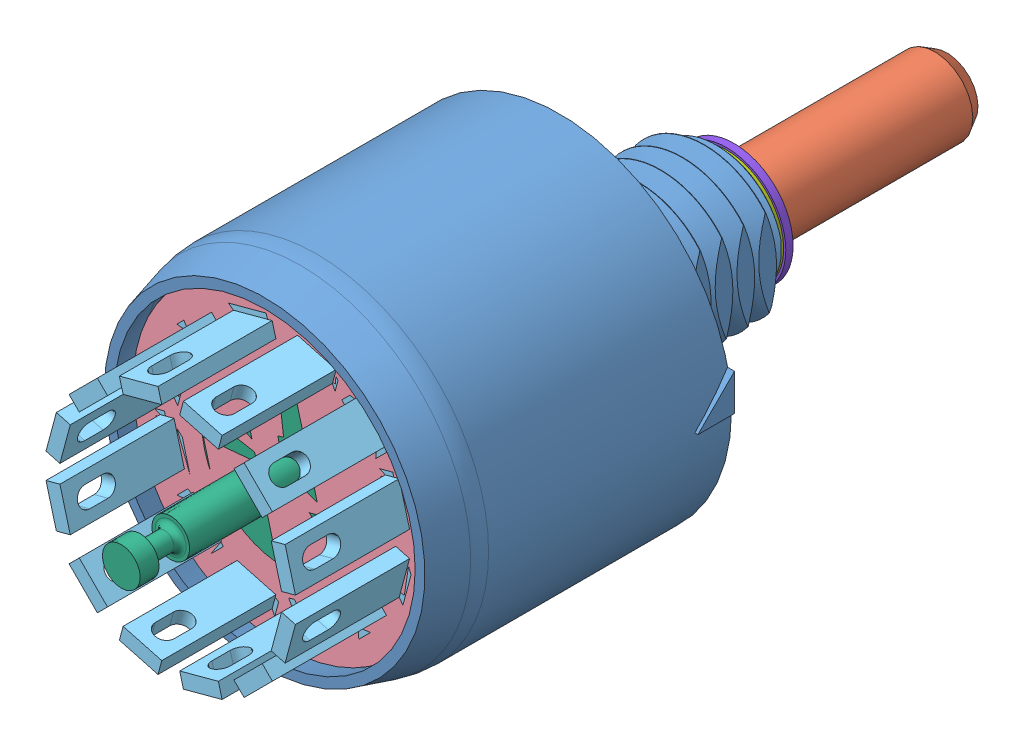
SolidWorks assembly 51M30-01-2-03N, configuration Default. Lengths in mm.
Overall size (16.37 16.39 34.37).
20 component instances, 8 part files, 0 mates.
Components (placement in the parent):
- 58R3008-X-1: 58R3008-X [Default] at origin size (14.45 14.33 19.06)
- 58J2001-1-1: 58J2001-1 [Default] x (0.258819 -0.965926 0) z (0 0 1) size (6.07 7.89 18.87)
- 58Z3130-1: 58Z3130 [Default] at (0 0 1.3207) x (0.258835 -0.965922 0) z (-0.965922 -0.258835 0) size (13.36 6.25 13.36)
- 58ZZ3040-5_ASM-1: 58ZZ3040-5_ASM [Default] at (0.0109 -0.0266 7.6015) x (-0.258835 0.965922 0) z (0.965922 0.258835 0) size (13.36 10.5 13.36)
  - 58ZZ3040-X_PLASTIC-1: 58ZZ3040-X_PLASTIC [Default] at origin size (13.36 3.7 13.36)
  - 50C3495-5-B-001-1: 50C3495-5-B-001 [Default] at (-4.2014 0.696 2.4257) x (0.5 0 0.866025) z (0.866025 0 -0.5) size (2 6.75 1.01)
  - 50C3495-5-B-001-2: 50C3495-5-B-001 [Default] at (-2.4257 0.696 4.2014) x (0.866025 0 0.5) z (0.5 0 -0.866025) size (2 6.75 1.01)
  - 50C3495-5-B-001-3: 50C3495-5-B-001 [Default] at (0 0.696 4.8514) x (1 0 0) z (0 0 -1) size (2 6.75 1.01)
  - 50C3495-5-B-001-4: 50C3495-5-B-001 [Default] at (2.4257 0.696 4.2014) x (0.866025 0 -0.5) z (-0.5 0 -0.866025) size (2 6.75 1.01)
  - 50C3495-5-B-001-5: 50C3495-5-B-001 [Default] at (4.2014 0.696 2.4257) x (0.5 0 -0.866025) z (-0.866025 0 -0.5) size (2 6.75 1.01)
  - 50C3495-5-B-001-6: 50C3495-5-B-001 [Default] at (4.8514 0.696 0) x (0 0 -1) z (-1 0 0) size (2 6.75 1.01)
  - 50C3495-5-B-001-7: 50C3495-5-B-001 [Default] at (4.2014 0.696 -2.4257) x (-0.5 0 -0.866025) z (-0.866025 0 0.5) size (2 6.75 1.01)
  - 50C3495-5-B-001-8: 50C3495-5-B-001 [Default] at (2.4257 0.696 -4.2014) x (-0.866025 0 -0.5) z (-0.5 0 0.866025) size (2 6.75 1.01)
  - 50C3495-5-B-001-9: 50C3495-5-B-001 [Default] at (0 0.696 -4.8514) x (-1 0 0) z (0 0 1) size (2 6.75 1.01)
  - 50C3495-5-B-001-10: 50C3495-5-B-001 [Default] at (-2.4257 0.696 -4.2014) x (-0.866025 0 0.5) z (0.5 0 0.866025) size (2 6.75 1.01)
  - 50C3495-5-B-001-11: 50C3495-5-B-001 [Default] at (-4.2014 0.696 -2.4257) x (-0.5 0 0.866025) z (0.866025 0 0.5) size (2 6.75 1.01)
  - 50C3495-5-B-001-12: 50C3495-5-B-001 [Default] at (-4.8514 0.696 0) x (0 0 1) z (1 0 0) size (2 6.75 1.01)
  - 58C3026-10-1: 58C3026-10 [Default] at (0 0.3302 0) size (7.16 8.59 7.16)
- 06J1025-12-1: 06J1025-12 [Default] at (0 0 -8.382) x (-1 0 0) z (0 0 -1) size (4.75 4.75 0.3)
- 58J2427-1: 58J2427 [Default] at (0 0 -8.6868) x (-1 0 0) z (0 0 -1) size (4.93 4.93 0.76)
